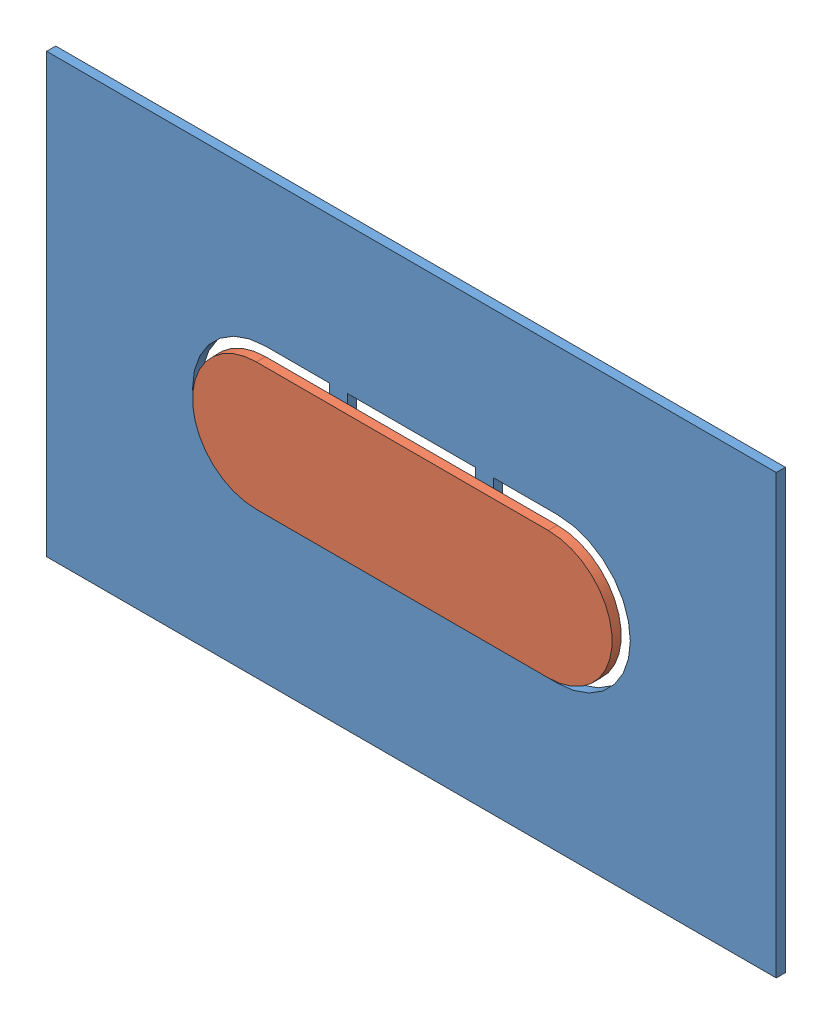
SolidWorks assembly arrayunlockhandle, configuration Default. Lengths in mm.
Overall size (127 76.2 3.17).
2 component instances, 2 part files, 4 mates.
Components (placement in the parent):
- InnerPlate-1: InnerPlate [Default] at (-5.8908 47.8943 87.8376) size (127 76.2 1.59)
- OuterPlate-1: OuterPlate [Default] at (32.2092 85.9943 89.4251) size (73.03 22.23 1.59)
Mates (geometry in assembly coordinates):
- Distance1: distance = 1.5875 mm anti-aligned: plane of OuterPlate-1 through (32.2092 74.8818 91.0126) normal (0 -1 0); plane of InnerPlate-1 through (68.7217 73.2943 89.4251) normal (0 1 0)
- Coincident2: coincident: line of InnerPlate-1 through (43.3217 73.2943 89.4251) axis (0 1 0); plane of OuterPlate-1
- LimitAngle2: limit planar angle = 0 rad anti-aligned: plane of OuterPlate-1 through (32.2092 85.9943 89.4251) normal (0 0 -1); plane of InnerPlate-1 through (-5.8908 47.8943 89.4251) normal (0 0 1)
- Coincident4: coincident anti-aligned: line of InnerPlate-1 through (43.3217 73.2943 89.4251) axis (0 1 0); line of OuterPlate-1 through (43.3217 97.1068 89.4251) axis (0 -1 0)
